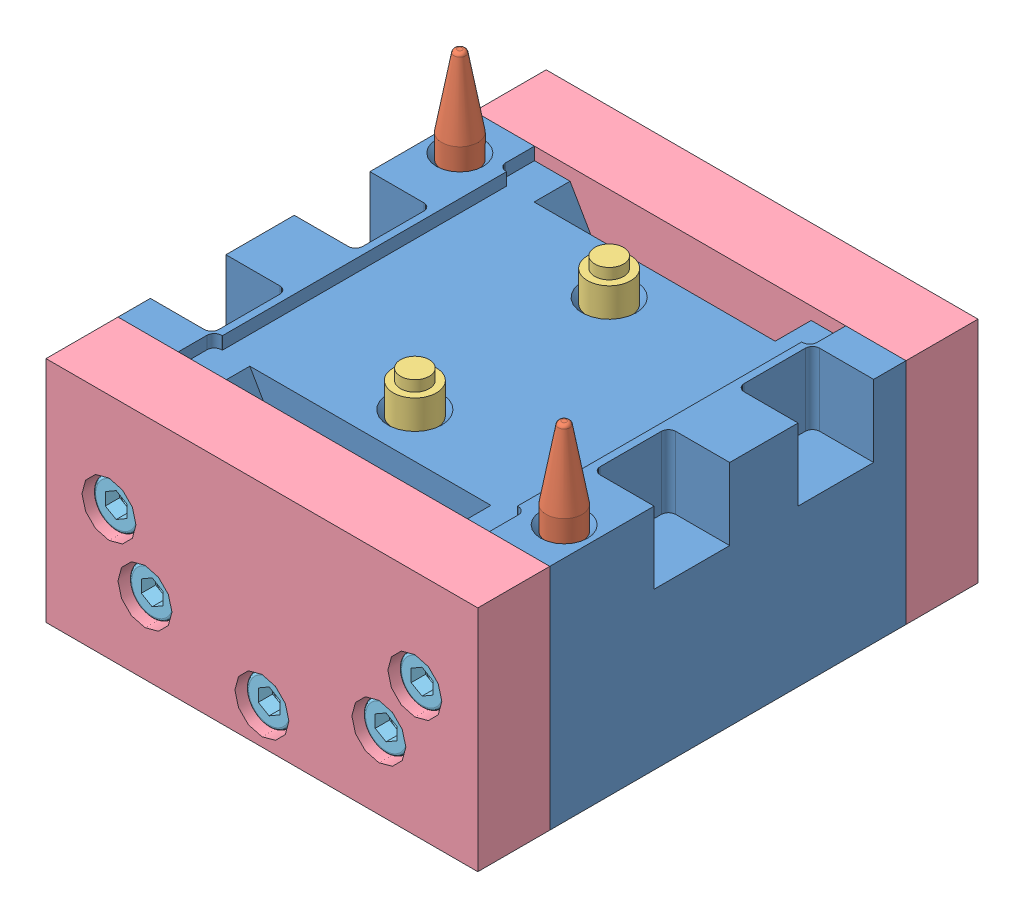
SolidWorks assembly сборка нижней пресс формы, configuration По умолчанию. Lengths in mm.
Overall size (120 88.5 139).
17 component instances, 5 part files, 35 mates.
Components (placement in the parent):
- Матрица пресс-формы трак-1: Матрица пресс-формы трак [По умолчанию] at (94.4955 113.7729 76.599) x (-1 0 0) z (0 -1 0) size (120 99 63.5)
- Направляющая-1: Направляющая [По умолчанию] at (134.3195 83.7729 119.5159) x (0 1 0) z (-0.942376 0 0.334555) size (55 10 10)
- Направляющая-2: Направляющая [По умолчанию] at (30.3195 83.7729 44.5159) x (0 1 0) z (-0.954844 0 0.297108) size (55 10 10)
- Подстановка-1: Подстановка [По умолчанию] at (85.2823 100.5229 55.4864) x (0 1 0) z (-0.987622 0 -0.156852) size (36.5 12 12)
- Подстановка-2: Подстановка [По умолчанию] at (83.6486 100.5229 111.7054) x (0 1 0) z (-0.443057 0 -0.896493) size (36.5 12 12)
- Боковина пресс-формы-1: Боковина пресс-формы [По умолчанию] at (82.3195 82.0229 131.5159) x (1 0 0) z (0 -1 0) size (120 20 63.5)
- Боковина пресс-формы-2: Боковина пресс-формы [По умолчанию] at (82.3195 82.0229 32.5159) x (-1 0 0) z (0 -1 0) size (120 20 63.5)
- болтец-1: болтец [EN ISO 4762 M8 x 25 - 25S] at (114.8195 70.2729 149.5159) x (0 0 -1) z (1 0 0) size (33 13 13)
- болтец-2: болтец [EN ISO 4762 M8 x 25 - 25S] at (82.3195 60.2729 149.5159) x (0 0 -1) z (1 0 0) size (33 13 13)
- болтец-3: болтец [EN ISO 4762 M8 x 25 - 25S] at (49.8195 70.2729 149.5159) x (0 0 -1) z (1 0 0) size (33 13 13)
- болтец-4: болтец [EN ISO 4762 M8 x 25 - 25N] at (124.8195 86.2729 149.5159) x (0 0 -1) z (1 0 0) size (33 13 13)
- болтец-5: болтец [EN ISO 4762 M8 x 25 - 25N] at (39.8195 86.2729 149.5159) x (0 0 -1) z (1 0 0) size (33 13 13)
- болтец-6: болтец [EN ISO 4762 M8 x 25 - 25N] at (39.8195 86.2729 14.5159) x (0 0 1) z (-1 0 0) size (33 13 13)
- болтец-7: болтец [EN ISO 4762 M8 x 25 - 25N] at (49.8195 70.2729 14.5159) x (0 0 1) z (-1 0 0) size (33 13 13)
- болтец-8: болтец [EN ISO 4762 M8 x 25 - 25N] at (82.3195 60.2729 14.5159) x (0 0 1) z (-1 0 0) size (33 13 13)
- болтец-9: болтец [EN ISO 4762 M8 x 25 - 25N] at (114.8195 70.2729 14.5159) x (0 0 1) z (-1 0 0) size (33 13 13)
- болтец-10: болтец [EN ISO 4762 M8 x 25 - 25N] at (124.8195 86.2729 14.5159) x (0 0 1) z (-1 0 0) size (33 13 13)
Mates (geometry in assembly coordinates):
- Совпадение1: coincident anti-aligned: plane of Матрица пресс-формы трак-1 through (134.3195 83.7729 119.5159) normal (0 1 0); plane of Направляющая-1 through (134.3195 83.7729 119.5159) normal (0 -1 0)
- Концентричный2: concentric anti-aligned: cylinder of Матрица пресс-формы трак-1 through (134.3195 83.7729 119.5159) axis (0 1 0) radius 5; cylinder of Направляющая-1 through (134.3195 83.7729 119.5159) axis (0 -1 0) radius 5
- Совпадение2: coincident anti-aligned: plane of Матрица пресс-формы трак-1 through (30.3195 83.7729 44.5159) normal (0 1 0); plane of Направляющая-2 through (30.3195 83.7729 44.5159) normal (0 -1 0)
- Концентричный3: concentric anti-aligned: cylinder of Матрица пресс-формы трак-1 through (30.3195 83.7729 44.5159) axis (0 1 0) radius 5; cylinder of Направляющая-2 through (30.3195 83.7729 44.5159) axis (0 -1 0) radius 5
- Совпадение3: coincident anti-aligned: plane of Матрица пресс-формы трак-1 through (82.3195 83.7729 55.0159) normal (0 1 0); plane of Подстановка-1 through (82.3195 83.7729 55.0159) normal (0 -1 0)
- Концентричный4: concentric anti-aligned: cylinder of Матрица пресс-формы трак-1 through (82.3195 83.7729 55.0159) axis (0 1 0) radius 6; cylinder of Подстановка-1 through (82.3195 83.7729 55.0159) axis (0 -1 0) radius 6
- Совпадение4: coincident anti-aligned: plane of Матрица пресс-формы трак-1 through (82.3195 83.7729 109.0159) normal (0 1 0); plane of Подстановка-2 through (82.3195 83.7729 109.0159) normal (0 -1 0)
- Концентричный5: concentric anti-aligned: cylinder of Матрица пресс-формы трак-1 through (82.3195 83.7729 109.0159) axis (0 1 0) radius 6; cylinder of Подстановка-2 through (82.3195 83.7729 109.0159) axis (0 -1 0) radius 6
- Совпадение7: coincident anti-aligned: plane of Матрица пресс-формы трак-1 through (142.3195 50.2729 131.5159) normal (0 0 1); plane of Боковина пресс-формы-1 through (82.3195 82.0229 131.5159) normal (0 0 -1)
- Концентричный8: concentric aligned: cylinder of Матрица пресс-формы трак-1 through (82.3195 60.2729 101.5159) axis (0 0 1) radius 3.4; cylinder of Боковина пресс-формы-1 through (82.3195 60.2729 151.5159) axis (0 0 1) radius 4.25
- Концентричный9: concentric aligned: cylinder of Матрица пресс-формы трак-1 through (82.3195 60.2729 62.5159) axis (0 0 -1) radius 3.4; cylinder of Боковина пресс-формы-2 through (82.3195 60.2729 12.5159) axis (0 0 -1) radius 4.25
- Совпадение8: coincident anti-aligned: plane of Матрица пресс-формы трак-1 through (142.3195 50.2729 32.5159) normal (0 0 -1); plane of Боковина пресс-формы-2 through (82.3195 82.0229 32.5159) normal (0 0 1)
- Параллельность2: parallel aligned: cylinder of Боковина пресс-формы-1 through (124.8195 86.2729 151.5159) axis (0 0 1) radius 4.25; cylinder of Матрица пресс-формы трак-1 through (124.8195 86.2729 101.5159) axis (0 0 1) radius 3.4
- Совпадение16: coincident aligned: plane of Матрица пресс-формы трак-1 through (142.3195 50.2729 32.5159) normal (1 0 0); plane of Боковина пресс-формы-1 through (142.3195 50.2729 151.5159) normal (1 0 0)
- Совпадение17: coincident aligned: plane of Матрица пресс-формы трак-1 through (142.3195 50.2729 32.5159) normal (1 0 0); plane of Боковина пресс-формы-2 through (142.3195 50.2729 12.5159) normal (1 0 0)
- Концентричный19: concentric aligned: cylinder of Боковина пресс-формы-1 through (114.8195 70.2729 151.5159) axis (0 0 1) radius 4.25; cylinder of socket head cap screw 4762_din-1 through (114.8195 70.2729 181.2659) axis (0 0 1) radius 6.5
- Совпадение20: coincident anti-aligned: plane of Боковина пресс-формы-1 through (119.0695 70.2729 141.5159) normal (0 0 1); plane of socket head cap screw 4762_din-1 through (114.8195 76.7729 141.5159) normal (0 0 -1)
- Концентричный20: concentric aligned: cylinder of Боковина пресс-формы-1 through (82.3195 60.2729 151.5159) axis (0 0 1) radius 7.5; cylinder of socket head cap screw 4762_din-2 through (82.3195 60.2729 181.2659) axis (0 0 1) radius 6.5
- Совпадение21: coincident anti-aligned: plane of Боковина пресс-формы-1 through (86.5695 60.2729 141.5159) normal (0 0 1); plane of socket head cap screw 4762_din-2 through (82.3195 66.7729 141.5159) normal (0 0 -1)
- Концентричный21: concentric aligned: cylinder of Боковина пресс-формы-1 through (49.8195 70.2729 151.5159) axis (0 0 1) radius 7.5; cylinder of socket head cap screw 4762_din-3 through (49.8195 70.2729 181.2659) axis (0 0 1) radius 6.5
- Совпадение22: coincident anti-aligned: plane of Боковина пресс-формы-1 through (54.0695 70.2729 141.5159) normal (0 0 1); plane of socket head cap screw 4762_din-3 through (49.8195 76.7729 141.5159) normal (0 0 -1)
- Концентричный23: concentric aligned: cylinder of Боковина пресс-формы-1 through (124.8195 86.2729 151.5159) axis (0 0 1) radius 4.25; cylinder of socket head cap screw 4762_din-4 through (124.8195 86.2729 181.2659) axis (0 0 1) radius 6.5
- Совпадение23: coincident anti-aligned: plane of Боковина пресс-формы-1 through (129.0695 86.2729 141.5159) normal (0 0 1); plane of socket head cap screw 4762_din-4 through (124.8195 92.7729 141.5159) normal (0 0 -1)
- Концентричный24: concentric aligned: cylinder of Боковина пресс-формы-1 through (39.8195 86.2729 151.5159) axis (0 0 1) radius 4.25; cylinder of socket head cap screw 4762_din-5 through (39.8195 86.2729 181.2659) axis (0 0 1) radius 6.5
- Совпадение24: coincident anti-aligned: plane of Боковина пресс-формы-1 through (44.0695 86.2729 141.5159) normal (0 0 1); plane of socket head cap screw 4762_din-5 through (39.8195 92.7729 141.5159) normal (0 0 -1)
- Концентричный25: concentric aligned: cylinder of Боковина пресс-формы-2 through (39.8195 86.2729 12.5159) axis (0 0 -1) radius 7.5; cylinder of socket head cap screw 4762_din-6 through (39.8195 86.2729 -17.2341) axis (0 0 -1) radius 6.5
- Совпадение25: coincident anti-aligned: plane of Боковина пресс-формы-2 through (35.5695 86.2729 22.5159) normal (0 0 -1); plane of socket head cap screw 4762_din-6 through (39.8195 92.7729 22.5159) normal (0 0 1)
- Концентричный26: concentric aligned: cylinder of Боковина пресс-формы-2 through (49.8195 70.2729 12.5159) axis (0 0 -1) radius 4.25; cylinder of socket head cap screw 4762_din-7 through (49.8195 70.2729 -17.2341) axis (0 0 -1) radius 6.5
- Совпадение26: coincident anti-aligned: plane of Боковина пресс-формы-2 through (45.5695 70.2729 22.5159) normal (0 0 -1); plane of socket head cap screw 4762_din-7 through (49.8195 76.7729 22.5159) normal (0 0 1)
- Концентричный27: concentric aligned: cylinder of Боковина пресс-формы-2 through (82.3195 60.2729 12.5159) axis (0 0 -1) radius 7.5; cylinder of socket head cap screw 4762_din-8 through (82.3195 60.2729 -17.2341) axis (0 0 -1) radius 6.5
- Совпадение27: coincident anti-aligned: plane of Боковина пресс-формы-2 through (78.0695 60.2729 22.5159) normal (0 0 -1); plane of socket head cap screw 4762_din-8 through (82.3195 66.7729 22.5159) normal (0 0 1)
- Концентричный28: concentric aligned: cylinder of Боковина пресс-формы-2 through (114.8195 70.2729 12.5159) axis (0 0 -1) radius 4.25; cylinder of socket head cap screw 4762_din-9 through (114.8195 70.2729 -17.2341) axis (0 0 -1) radius 6.5
- Совпадение28: coincident anti-aligned: plane of Боковина пресс-формы-2 through (110.5695 70.2729 22.5159) normal (0 0 -1); plane of socket head cap screw 4762_din-9 through (114.8195 76.7729 22.5159) normal (0 0 1)
- Концентричный29: concentric aligned: cylinder of Боковина пресс-формы-2 through (124.8195 86.2729 12.5159) axis (0 0 -1) radius 7.5; cylinder of socket head cap screw 4762_din-10 through (124.8195 86.2729 -17.2341) axis (0 0 -1) radius 6.5
- Совпадение29: coincident anti-aligned: plane of Боковина пресс-формы-2 through (120.5695 86.2729 22.5159) normal (0 0 -1); plane of болтец-10 through (124.8195 92.7729 22.5159) normal (0 0 1)
